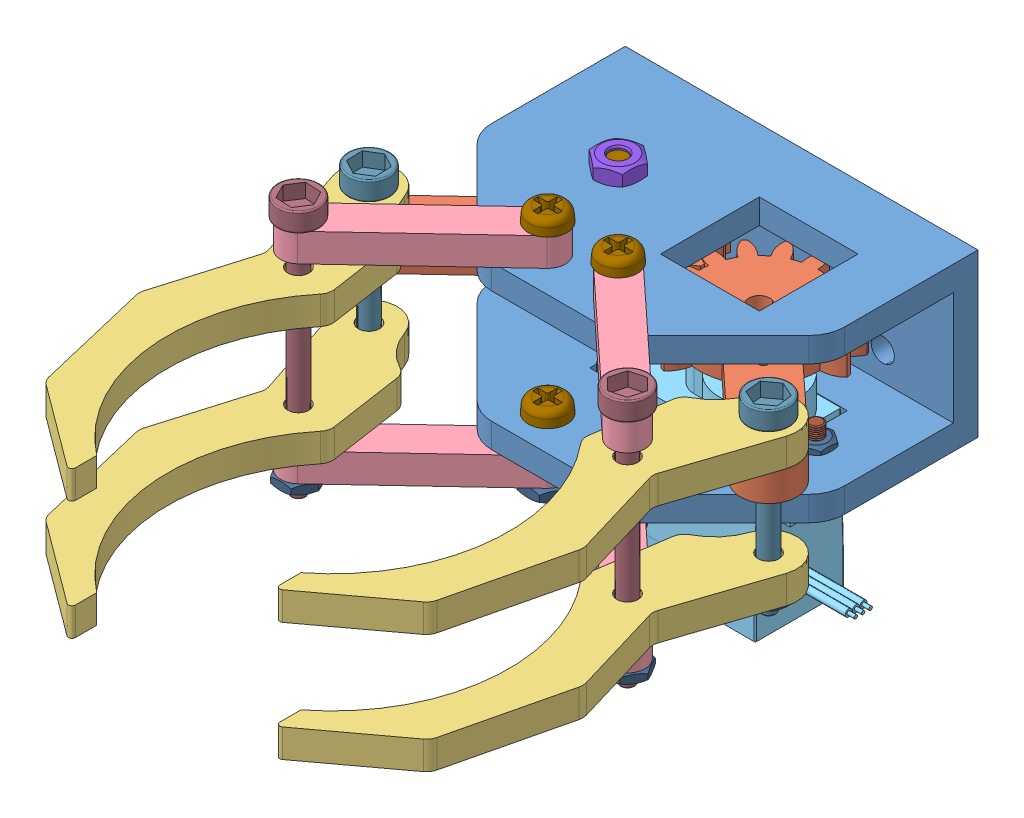
SolidWorks assembly 机械臂, configuration 默认. Lengths in mm.
Overall size (77.1 48.36 89.05).
38 component instances, 14 part files, 135 mates.
Components (placement in the parent):
- 支撑板（改）-1: 支撑板（改） [默认] at (92.699 11.5 0) x (0 0 -1) z (1 0 0) size (36 23 50)
- 齿轮传动杆-6: 齿轮传动杆 [默认] at (109.3845 -5.9575 25.747) x (0 1 0) z (0.609506 0 0.792782) size (4 39.97 22.17)
- 齿轮传动杆-7: 齿轮传动杆 [默认] at (137.3064 -6.0175 13.6459) x (0 1 0) z (0.748833 0 -0.662759) size (4 39.97 22.17)
- 机械手爪（改）-1: 机械手爪（改） [默认] at (126.8226 16.84 9.7612) x (-1 0 0) z (0 1 0) size (17.85 59.94 4)
- 机械手爪（改）-2: 机械手爪（改） [默认] at (108.6689 20.84 9.8615) x (1 0 0) z (0 -1 0) size (17.85 59.94 4)
- 连杆（改）-1: 连杆（改） [默认] at (131.861 27 39.5033) x (-0.680266 0 0.732966) z (0 -1 0) size (5 30 4)
- 连杆（改）-2: 连杆（改） [默认] at (103.5837 23 39.5535) x (0.684277 0 0.729222) z (0 1 0) size (5 30 4)
- 连杆（改）-3: 连杆（改） [默认] at (131.861 0 39.5033) x (0.680266 0 -0.732966) z (0 -1 0) size (5 30 4)
- 连杆（改）-4: 连杆（改） [默认] at (103.5837 0 39.5535) x (-0.684277 0 -0.729222) z (0 -1 0) size (5 30 4)
- 机械手爪（改）-3: 机械手爪（改） [默认] at (126.8226 0 9.7612) x (-1 0 0) z (0 1 0) size (17.85 59.94 4)
- 机械手爪（改）-4: 机械手爪（改） [默认] at (108.6689 4 9.8615) x (1 0 0) z (0 -1 0) size (17.85 59.94 4)
- SG90-2: SG90 [Default] at (126.294 -2.32 16) x (-1 0 0) z (0 0 -1) size (36.67 29.95 12.59)
  - Tower Pro 9g Micro Servo SG90-1: Tower Pro 9g Micro Servo SG90 [Default] at origin size (36.67 29.95 12.59)
- SG90 plastic Horn-1: SG90 plastic Horn [Default] at (127.699 10.84 16) x (0.605346 0 0.795962) z (-0.795962 0 0.605346) size (19.4 4 7.07)
- plain washers--product grade c gb-2: plain washers--product grade c gb [GB_FASTENER_WASHER_SMWC 3] at (107.699 17.4 16) x (-0.69769 0 0.716399) z (0 1 0) size (7 7 0.5)
- hex nuts, style 1-grades ab gb-2: hex nuts, style 1-grades ab gb [GB_FASTENER_NUT_SNAB1 M3-N] at (107.699 23 16) x (-0.923728 0 0.383049) z (0 -1 0) size (6.35 5.5 2.4)
- cross recessed cheese head screws gb-3: cross recessed cheese head screws gb [GB_CROSS_SCREWS_TYPE2 M3X12-12  H type-C] at (107.699 10.9 16) x (0 1 0) z (0 0 1) size (14.01 5.5 5.5)
- hex thin nuts-grades ab-chamfered gb-1: hex thin nuts-grades ab-chamfered gb [GB_FASTENER_NUT_STNAB M2-N] at (135.744 3.5 16) x (0.837169 0 0.546944) z (0 -1 0) size (4.62 4 1.2)
- hex thin nuts-grades ab-chamfered gb-2: hex thin nuts-grades ab-chamfered gb [GB_FASTENER_NUT_STNAB M2-N] at (108.074 3.5 16) x (0.837169 0 0.546944) z (0 -1 0) size (4.62 4 1.2)
- cross recessed countersunk head screws gb2-3: cross recessed countersunk head screws gb2 [GB_CROSS_SCREWS_TYPE10 M2X10-8.8-H1-S] at (108.074 -3.52 16) x (0 1 0) z (0.546944 0 -0.837169) size (10 3.5 3.5)
- cross recessed countersunk head screws gb2-4: cross recessed countersunk head screws gb2 [GB_CROSS_SCREWS_TYPE10 M2X10-8.8-H1-S] at (135.744 -3.52 16) x (0 1 0) z (0 0 1) size (10 3.5 3.5)
- 2.1支撑垫片-1: 2.1支撑垫片 [默认] at (107.699 19.5 16) x (1 0 0) z (0 -1 0) size (5 5 2.1)
- hex thin nuts-grades ab-chamfered gb-3: hex thin nuts-grades ab-chamfered gb [GB_FASTENER_NUT_STNAB M2.5-N] at (141.0231 -4 48.0066) x (1 0 0) z (0 1 0) size (5.77 5 1.6)
- hex thin nuts-grades ab-chamfered gb-4: hex thin nuts-grades ab-chamfered gb [GB_FASTENER_NUT_STNAB M2.5-N] at (89.4684 0 33.1069) x (0.977048 0 0.213019) z (0 1 0) size (5.77 5 1.6)
- hex thin nuts-grades ab-chamfered gb-5: hex thin nuts-grades ab-chamfered gb [GB_FASTENER_NUT_STNAB M2.5-N] at (146.0231 -1.6 33.0066) x (0.933255 0 -0.359214) z (0 -1 0) size (5.77 5 1.6)
- hex thin nuts-grades ab-chamfered gb-6: hex thin nuts-grades ab-chamfered gb [GB_FASTENER_NUT_STNAB M2.5-N] at (94.4684 -4 48.1069) x (1 0 0) z (0 1 0) size (5.77 5 1.6)
- 30限位螺栓-3: 30限位螺栓 [默认] at (141.0231 29.7 48.0066) x (-0.844413 0 -0.535692) z (-0.535692 0 0.844413) size (5.9 36.7 5.9)
- 30限位螺栓-4: 30限位螺栓 [默认] at (94.4684 29.7 48.1069) x (0.335228 0 -0.942137) z (-0.942137 0 -0.335228) size (5.9 36.7 5.9)
- 20限位螺栓-3: 20限位螺栓 [默认] at (146.0231 23.54 33.0066) x (0.648707 0 -0.761038) z (-0.761038 0 -0.648707) size (5.9 26.7 5.9)
- 20限位螺栓-4: 20限位螺栓 [默认] at (89.4684 23.54 33.1069) x (0.708583 0 -0.705627) z (-0.705627 0 -0.708583) size (5.9 26.7 5.9)
- cross recessed cheese head screws gb-5: cross recessed cheese head screws gb [GB_CROSS_SCREWS_TYPE2 M3X10-10  H type-C] at (112.699 5.5 31) x (0 -1 0) z (0 0 1) size (12.01 5.5 5.5)
- cross recessed cheese head screws gb-6: cross recessed cheese head screws gb [GB_CROSS_SCREWS_TYPE2 M3X10-10  H type-C] at (122.699 5.5 31) x (0 -1 0) z (0 0 1) size (12.01 5.5 5.5)
- cross recessed cheese head screws gb-7: cross recessed cheese head screws gb [GB_CROSS_SCREWS_TYPE2 M3X10-10  H type-C] at (122.699 29 31) x (0 -1 0) z (0 0 1) size (12.01 5.5 5.5)
- cross recessed cheese head screws gb-8: cross recessed cheese head screws gb [GB_CROSS_SCREWS_TYPE2 M3X10-10  H type-C] at (112.699 29 31) x (0 -1 0) z (0 0 1) size (12.01 5.5 5.5)
- hex thin nuts-grades ab-chamfered gb-7: hex thin nuts-grades ab-chamfered gb [GB_FASTENER_NUT_STNAB M3-N] at (122.699 17.7 31) x (1 0 0) z (0 -1 0) size (6.35 5.5 1.8)
- hex thin nuts-grades ab-chamfered gb-9: hex thin nuts-grades ab-chamfered gb [GB_FASTENER_NUT_STNAB M3-N] at (112.699 17.7 31) x (1 0 0) z (0 -1 0) size (6.35 5.5 1.8)
- hex thin nuts-grades ab-chamfered gb-11: hex thin nuts-grades ab-chamfered gb [GB_FASTENER_NUT_STNAB M3-N] at (122.699 -5.8 31) x (1 0 0) z (0 -1 0) size (6.35 5.5 1.8)
- hex thin nuts-grades ab-chamfered gb-12: hex thin nuts-grades ab-chamfered gb [GB_FASTENER_NUT_STNAB M3-N] at (112.699 -4 31) x (1 0 0) z (0 1 0) size (6.35 5.5 1.8)
Mates (geometry in assembly coordinates):
- 重合1: coincident anti-aligned: plane of 支撑板（改）-1 through (142.699 0 0) normal (0 -1 0)
- 重合2: coincident anti-aligned: plane of 支撑板（改）-1 through (142.699 23 45) normal (0 1 0); plane of 零件2-1 through (70.0462 31.0635 138.7795) normal (0 -1 0)
- 同心1: concentric aligned: cylinder of 支撑板（改）-1 through (127.699 89.5 16) axis (0 -1 0) radius 1.5; cylinder of 零件2-1 through (70.0462 81.0636 138.7795) axis (0 -1 0) radius 1.5
- 重合3: coincident anti-aligned: plane of 支撑板（改）-1 through (142.699 23 45) normal (0 1 0); plane of 零件2-2 through (70.0462 31.0635 118.7795) normal (0 -1 0)
- 同心2: concentric anti-aligned: cylinder of 支撑板（改）-1 through (107.699 89.5 16) axis (0 -1 0) radius 1.5; cylinder of 零件2-2 through (70.0462 -14.9365 118.7795) axis (0 1 0) radius 1.5
- 重合6: coincident anti-aligned: plane of 支撑板（改）-1 through (142.699 23 45) normal (0 1 0); plane of 零件2-3 through (70.0462 31.0635 118.7795) normal (0 -1 0)
- 同心3: concentric anti-aligned: cylinder of 支撑板（改）-1 through (107.699 89.5 16) axis (0 -1 0) radius 1.5; cylinder of 零件2-3 through (70.0462 -14.9365 118.7795) axis (0 1 0) radius 1.5
- 同心9: concentric aligned: cylinder of 支撑板（改）-1 through (107.699 89.5 16) axis (0 -1 0) radius 1.5; cylinder of 齿轮传动杆-6 through (107.699 62.9001 16) axis (0 -1 0) radius 1.5
- 重合13: coincident anti-aligned: plane of 齿轮传动杆-7 through (127.699 16.84 16) normal (0 1 0); plane of 机械手爪（改）-2 through (118.6269 16.84 65.7764) normal (0 -1 0)
- 同心11: concentric aligned: cylinder of 齿轮传动杆-6 through (89.4684 12.9 33.1069) axis (0 1 0) radius 1.5; cylinder of 机械手爪（改）-2 through (89.4684 16.84 33.1069) axis (0 1 0) radius 1.5
- 重合14: coincident anti-aligned: plane of 齿轮传动杆-7 through (127.699 16.84 16) normal (0 1 0); plane of 机械手爪（改）-1 through (116.8646 16.84 65.6761) normal (0 -1 0)
- 同心12: concentric anti-aligned: cylinder of 齿轮传动杆-7 through (146.0231 12.84 33.0066) axis (0 1 0) radius 1.5; cylinder of 机械手爪（改）-1 through (146.0231 20.84 33.0066) axis (0 -1 0) radius 1.5
- 同心13: concentric anti-aligned: cylinder of 机械手爪（改）-1 through (141.0231 20.84 48.0066) axis (0 -1 0) radius 1.5; cylinder of 连杆（改）-1 through (141.0231 23 48.0066) axis (0 1 0) radius 1.5
- 同心14: concentric anti-aligned: cylinder of 支撑板（改）-1 through (122.699 89.5 31) axis (0 -1 0) radius 1.5; cylinder of 连杆（改）-1 through (122.699 23 31) axis (0 1 0) radius 1.5
- 同心15: concentric anti-aligned: cylinder of 机械手爪（改）-2 through (94.4684 16.84 48.1069) axis (0 1 0) radius 1.5; cylinder of 连杆（改）-2 through (94.4684 27 48.1069) axis (0 -1 0) radius 1.5
- 同心16: concentric aligned: cylinder of 支撑板（改）-1 through (112.699 89.5 31) axis (0 -1 0) radius 1.5; cylinder of 连杆（改）-2 through (112.699 27 31) axis (0 -1 0) radius 1.5
- 重合17: coincident anti-aligned: plane of 连杆（改）-3 through (122.699 0 31) normal (0 1 0); plane of 机械手爪（改）-3 through (116.8646 0 65.6761) normal (0 -1 0)
- 同心19: concentric anti-aligned: cylinder of 连杆（改）-3 through (141.0231 -4 48.0066) axis (0 1 0) radius 1.5; cylinder of 机械手爪（改）-3 through (141.0231 4 48.0066) axis (0 -1 0) radius 1.5
- 重合20: coincident anti-aligned: plane of 连杆（改）-4 through (94.4684 0 48.1069) normal (0 1 0); plane of 机械手爪（改）-4 through (118.6269 0 65.7764) normal (0 -1 0)
- 同心24: concentric anti-aligned: cylinder of 支撑板（改）-1 through (122.699 89.5 31) axis (0 -1 0) radius 1.5; cylinder of 连杆（改）-3 through (122.699 -4 31) axis (0 1 0) radius 1.5
- 同心25: concentric anti-aligned: cylinder of 支撑板（改）-1 through (112.699 89.5 31) axis (0 -1 0) radius 1.5; cylinder of 连杆（改）-4 through (112.699 -4 31) axis (0 1 0) radius 1.5
- 同心30: concentric anti-aligned: cylinder of 机械手爪（改）-1 through (141.0231 20.84 48.0066) axis (0 -1 0) radius 1.5; cylinder of 连杆-2 through (50.1174 -3 156.1886) axis (0 1 0) radius 1.5
- 同心31: concentric anti-aligned: cylinder of 机械手爪（改）-3 through (141.0231 4 48.0066) axis (0 -1 0) radius 1.5; cylinder of 连杆-2 through (50.1174 -3 156.1886) axis (0 1 0) radius 1.5
- 同心32: concentric anti-aligned: cylinder of 机械手爪（改）-1 through (146.0231 20.84 33.0066) axis (0 -1 0) radius 1.5; cylinder of 连杆-4 through (62.6978 0 163.3985) axis (0 1 0) radius 1.5
- 同心33: concentric anti-aligned: cylinder of 机械手爪（改）-3 through (146.0231 4 33.0066) axis (0 -1 0) radius 1.5; cylinder of 连杆-4 through (62.6978 0 163.3985) axis (0 1 0) radius 1.5
- 同心34: concentric anti-aligned: cylinder of 机械手爪（改）-4 through (89.4684 0 33.1069) axis (0 1 0) radius 1.5; cylinder of 连杆-5 through (62.5628 32 94.1848) axis (0 -1 0) radius 1.5
- 同心35: concentric anti-aligned: cylinder of 机械手爪（改）-2 through (89.4684 16.84 33.1069) axis (0 1 0) radius 1.5; cylinder of 连杆-5 through (62.5628 32 94.1848) axis (0 -1 0) radius 1.5
- 同心36: concentric anti-aligned: cylinder of 机械手爪（改）-4 through (94.4684 0 48.1069) axis (0 1 0) radius 1.5; cylinder of 连杆-6 through (49.9764 29.5 101.3843) axis (0 -1 0) radius 1.5
- 同心37: concentric anti-aligned: cylinder of 机械手爪（改）-2 through (94.4684 16.84 48.1069) axis (0 1 0) radius 1.5; cylinder of 连杆-6 through (49.9764 29.5 101.3843) axis (0 -1 0) radius 1.5
- 重合22: coincident aligned: plane of 机械手爪（改）-3 through (116.8646 0 65.6761) normal (0 -1 0); plane of 连杆-4 through (62.6978 0 163.3985) normal (0 -1 0)
- 重合23: coincident aligned: plane of 连杆（改）-3 through (122.699 -4 31) normal (0 -1 0); plane of 连杆-2 through (50.1174 -3 156.1886) normal (0 -1 0)
- 重合25: coincident aligned: plane of 连杆-5 through (62.5628 0 94.1848) normal (0 -1 0); plane of 机械手爪（改）-4 through (118.6269 0 65.7764) normal (0 -1 0)
- 重合26: coincident aligned: plane of 连杆（改）-4 through (94.4684 -4 48.1069) normal (0 -1 0); plane of 连杆-6 through (49.9764 -2.5 101.3843) normal (0 -1 0)
- 同心39: concentric aligned: cylinder of 连杆（改）-4 through (94.4684 -4 48.1069) axis (0 1 0) radius 1.5; cylinder of 机械手爪（改）-4 through (94.4684 0 48.1069) axis (0 1 0) radius 1.5
- 齿轮配合3: gear = 20 : 20 mm: circle of 零件2-5; circle of 零件2-4
- 重合32: coincident anti-aligned: plane of 支撑板（改）-1 through (142.699 0 0) normal (0 -1 0); plane of SG90-2/Tower Pro 9g Micro Servo SG90-1 through (138.064 0 9.705) normal (0 1 0)
- 同心41: concentric aligned: cylinder of 支撑板（改）-1 through (108.074 10 16) axis (0 -1 0) radius 1; cylinder of SG90-2/Tower Pro 9g Micro Servo SG90-1 through (108.074 8.34 16) axis (0 -1 0) radius 0.975
- 同心42: concentric aligned: cylinder of 支撑板（改）-1 through (135.744 10 16) axis (0 -1 0) radius 1; cylinder of SG90-2/Tower Pro 9g Micro Servo SG90-1 through (135.744 8.34 16) axis (0 -1 0) radius 0.975
- 重合35: coincident anti-aligned: plane of SG90-2/Tower Pro 9g Micro Servo SG90-1 through (127.699 11.29 16) normal (0 1 0); plane of SG90 plastic Horn-1 through (128.4526 11.29 16.991) normal (0 -1 0)
- 同心44: concentric aligned: cylinder of SG90-2/Tower Pro 9g Micro Servo SG90-1 through (127.699 7.34 16) axis (0 1 0) radius 2.3; cylinder of SG90 plastic Horn-1 through (127.699 65.84 16) axis (0 1 0) radius 2.375
- 重合42: coincident anti-aligned: plane of 支撑板（改）-1 through (142.699 19.5 45) normal (0 -1 0); plane of plain washers--product grade c gb-5 through (67.0462 25.4 138.7795) normal (0 1 0)
- 同心45: concentric anti-aligned: cylinder of 支撑板（改）-1 through (127.699 89.5 16) axis (0 -1 0) radius 1.5; cylinder of plain washers--product grade c gb-5 through (67.0462 24.9 138.7795) axis (0 1 0) radius 1.7
- 重合44: coincident anti-aligned: plane of 齿轮传动杆-7 through (127.699 16.84 16) normal (0 1 0); plane of plain washers--product grade c gb-5 through (67.0462 24.9 138.7795) normal (0 -1 0)
- 同心46: concentric anti-aligned: cylinder of 支撑板（改）-1 through (107.699 89.5 16) axis (0 -1 0) radius 1.5; cylinder of plain washers--product grade c gb-2 through (107.699 16.9 16) axis (0 1 0) radius 1.7
- 重合46: coincident anti-aligned: plane of 齿轮传动杆-6 through (107.699 16.9 16) normal (0 1 0); plane of plain washers--product grade c gb-5 through (67.0462 24.9 138.7795) normal (0 -1 0)
- 重合47: coincident anti-aligned: plane of 支撑板（改）-1 through (142.699 23 45) normal (0 1 0); plane of 连杆（改）-1 through (141.0231 23 48.0066) normal (0 -1 0)
- 重合48: coincident anti-aligned: plane of 支撑板（改）-1 through (142.699 23 45) normal (0 1 0); plane of 连杆（改）-2 through (94.4684 23 48.1069) normal (0 -1 0)
- 重合49: coincident anti-aligned: plane of 齿轮传动杆-6 through (107.699 12.9 16) normal (0 -1 0); plane of cross recessed cheese head screws gb-1 through (67.0462 13.4 116.9795) normal (0 1 0)
- 同心47: concentric anti-aligned: cylinder of 支撑板（改）-1 through (107.699 89.5 16) axis (0 -1 0) radius 1.5; cylinder of cross recessed cheese head screws gb-1 through (67.0462 15.9158 118.7795) axis (0 1 0) radius 1.5
- 重合51: coincident anti-aligned: plane of 齿轮传动杆-6 through (107.699 12.9 16) normal (0 -1 0); plane of cross recessed cheese head screws gb-3 through (105.899 12.9 16) normal (0 1 0)
- 同心50: concentric anti-aligned: cylinder of 支撑板（改）-1 through (107.699 89.5 16) axis (0 -1 0) radius 1.5; cylinder of cross recessed cheese head screws gb-3 through (107.699 15.4158 16) axis (0 1 0) radius 1.5
- 重合52: coincident anti-aligned: plane of 支撑板（改）-1 through (142.699 23 45) normal (0 1 0); plane of hex nuts, style 1-grades ab gb-2 through (109.8057 23 21.0805) normal (0 -1 0)
- 同心51: concentric anti-aligned: cylinder of hex nuts, style 1-grades ab gb-2 through (107.699 25.4 16) axis (0 -1 0) radius 1.2295; cylinder of cross recessed cheese head screws gb-3 through (107.699 15.4158 16) axis (0 1 0) radius 1.5
- 重合54: coincident anti-aligned: plane of SG90-2/Tower Pro 9g Micro Servo SG90-1 through (110.394 -2.32 9.705) normal (0 -1 0); circle of cross recessed countersunk head screws gb2-2
- 同心52: concentric anti-aligned: cylinder of SG90-2/Tower Pro 9g Micro Servo SG90-1 through (108.074 8.34 16) axis (0 -1 0) radius 0.975; cylinder of cross recessed countersunk head screws gb2-2 through (67.0462 0.9958 120.5595) axis (0 1 0) radius 1
- 重合55: coincident anti-aligned: plane of SG90-2/Tower Pro 9g Micro Servo SG90-1 through (138.064 -2.32 9.705) normal (0 -1 0); circle of cross recessed countersunk head screws gb2-1
- 同心53: concentric anti-aligned: cylinder of SG90-2/Tower Pro 9g Micro Servo SG90-1 through (135.744 8.34 16) axis (0 -1 0) radius 0.975; cylinder of cross recessed countersunk head screws gb2-1 through (67.0462 0.9958 148.2295) axis (0 1 0) radius 1.75
- 重合56: coincident anti-aligned: plane of 支撑板（改）-1 through (142.699 3.5 3.5) normal (0 1 0); plane of hex thin nuts-grades ab-chamfered gb-2 through (106.2678 3.5 12.431) normal (0 -1 0)
- 同心54: concentric aligned: circle of cross recessed countersunk head screws gb2-2; cylinder of hex thin nuts-grades ab-chamfered gb-2 through (108.074 4.7 16) axis (0 -1 0) radius 0.7835
- 重合57: coincident anti-aligned: plane of SG90-2/Tower Pro 9g Micro Servo SG90-1 through (110.394 -2.32 9.705) normal (0 -1 0); circle of cross recessed countersunk head screws gb2-3
- 同心55: concentric aligned: cylinder of SG90-2/Tower Pro 9g Micro Servo SG90-1 through (108.074 8.34 16) axis (0 -1 0) radius 0.975; circle of cross recessed countersunk head screws gb2-3
- 重合58: coincident anti-aligned: plane of SG90-2/Tower Pro 9g Micro Servo SG90-1 through (138.064 -2.32 9.705) normal (0 -1 0); circle of cross recessed countersunk head screws gb2-4
- 同心56: concentric anti-aligned: cylinder of SG90-2/Tower Pro 9g Micro Servo SG90-1 through (135.744 8.34 16) axis (0 -1 0) radius 0.975; cylinder of cross recessed countersunk head screws gb2-4 through (135.744 0.9958 16) axis (0 1 0) radius 1.75
- 重合59: coincident anti-aligned: plane of 支撑板（改）-1 through (142.699 3.5 3.5) normal (0 1 0); plane of hex thin nuts-grades ab-chamfered gb-1 through (133.9378 3.5 12.431) normal (0 -1 0)
- 同心57: concentric aligned: cylinder of hex thin nuts-grades ab-chamfered gb-1 through (135.744 4.7 16) axis (0 -1 0) radius 0.7835; circle of cross recessed countersunk head screws gb2-4
- 重合61: coincident anti-aligned: plane of 齿轮传动杆-6 through (107.699 16.9 16) normal (0 1 0); plane of plain washers--product grade c gb-2 through (107.699 16.9 16) normal (0 -1 0)
- 重合63: coincident anti-aligned: plane of 齿轮传动杆-7 through (127.699 12.84 16) normal (0 -1 0); plane of SG90 plastic Horn-1 through (129.8389 12.84 18.8137) normal (0 1 0)
- 重合64: coincident anti-aligned: plane of 支撑板（改）-1 through (142.699 0 0) normal (0 -1 0); plane of 连杆（改）-4 through (94.4684 0 48.1069) normal (0 1 0)
- 重合66: coincident anti-aligned: plane of 支撑板（改）-1 through (142.699 0 0) normal (0 -1 0); plane of 连杆（改）-3 through (122.699 0 31) normal (0 1 0)
- 重合67: coincident anti-aligned: plane of 连杆（改）-3 through (122.699 -4 31) normal (0 -1 0); circle of slotted ctsk screws waisted shank gb-3
- 重合68: coincident anti-aligned: plane of 连杆（改）-1 through (141.0231 27 48.0066) normal (0 1 0); plane of slotted screws with waisted shank gb-5 through (49.0811 23.9 146.4039) normal (0 -1 0)
- 重合71: coincident anti-aligned: plane of 支撑板（改）-1 through (142.699 19.5 45) normal (0 -1 0); plane of 0.1垫片-1 through (107.699 19.5 16) normal (0 1 0)
- 同心58: concentric aligned: cylinder of cross recessed cheese head screws gb-3 through (107.699 15.4158 16) axis (0 1 0) radius 1.5; cylinder of 0.1垫片-1 through (107.699 17.4 16) axis (0 1 0) radius 1.5
- 重合72: coincident anti-aligned: plane of plain washers--product grade c gb-2 through (107.699 17.4 16) normal (0 1 0); plane of 0.1垫片-1 through (107.699 17.4 16) normal (0 -1 0)
- 重合73: coincident anti-aligned: plane of 连杆（改）-3 through (122.699 -4 31) normal (0 -1 0); plane of 25限位螺栓-1 through (31.7301 -4 138.5188) normal (0 1 0)
- 同心59: concentric anti-aligned: cylinder of 连杆（改）-3 through (141.0231 -4 48.0066) axis (0 1 0) radius 1.5; cylinder of 25限位螺栓-1 through (31.7301 26 138.5188) axis (0 -1 0) radius 1.5
- 同心61: concentric aligned: cylinder of 机械手爪（改）-1 through (141.0231 20.84 48.0066) axis (0 -1 0) radius 1.5; cylinder of 25限位螺栓-1 through (31.7301 26 138.5188) axis (0 -1 0) radius 1.5
- 重合76: coincident anti-aligned: plane of 25限位螺栓-1 through (31.7301 26 138.5188) normal (0 1 0); plane of hex thin nuts-grades ab-chamfered gb-3 through (136.693 -5.6 50.5066) normal (0 -1 0)
- 同心63: concentric anti-aligned: cylinder of 25限位螺栓-1 through (31.7301 31 138.5188) axis (0 -1 0) radius 1.25; cylinder of hex thin nuts-grades ab-chamfered gb-3 through (141.0231 -5.6 48.0066) axis (0 1 0) radius 1.0065
- 重合77: coincident anti-aligned: plane of 机械手爪（改）-4 through (118.6269 0 65.7764) normal (0 -1 0); plane of 25限位螺栓1-1 through (45.1123 0 106.7836) normal (0 1 0)
- 同心64: concentric anti-aligned: cylinder of 机械手爪（改）-4 through (89.4684 0 33.1069) axis (0 1 0) radius 1.5; cylinder of 25限位螺栓1-1 through (45.1123 25 106.7836) axis (0 -1 0) radius 1.5
- 同心65: concentric anti-aligned: cylinder of 齿轮传动杆-6 through (89.4684 12.9 33.1069) axis (0 1 0) radius 1.5; cylinder of 25限位螺栓1-1 through (45.1123 25 106.7836) axis (0 -1 0) radius 1.5
- 重合78: coincident anti-aligned: plane of hex thin nuts-grades ab-chamfered gb-4 through (84.7051 -1.6 34.6271) normal (0 -1 0); plane of 25限位螺栓1-1 through (45.1123 25 106.7836) normal (0 1 0)
- 同心66: concentric aligned: circle of hex thin nuts-grades ab-chamfered gb-4; cylinder of 25限位螺栓1-1 through (45.1123 30 106.7836) axis (0 -1 0) radius 1.25
- 同心67: concentric anti-aligned: cylinder of 连杆（改）-4 through (94.4684 -4 48.1069) axis (0 1 0) radius 1.5; cylinder of 25限位螺栓-2 through (31.7089 55 119.2025) axis (0 -1 0) radius 1.5
- 重合80: coincident anti-aligned: plane of hex thin nuts-grades ab-chamfered gb-6 through (90.1383 -5.6 50.6069) normal (0 -1 0); plane of 25限位螺栓-2 through (31.7089 55 119.2025) normal (0 1 0)
- 同心68: concentric anti-aligned: cylinder of hex thin nuts-grades ab-chamfered gb-6 through (94.4684 -5.6 48.1069) axis (0 1 0) radius 1.0065; cylinder of 25限位螺栓-2 through (31.7089 60 119.2025) axis (0 -1 0) radius 1.25
- 重合81: coincident anti-aligned: plane of 机械手爪（改）-3 through (116.8646 0 65.6761) normal (0 -1 0); plane of 25限位螺栓1-2 through (43.4542 0 147.0508) normal (0 1 0)
- 同心69: concentric aligned: cylinder of 机械手爪（改）-3 through (146.0231 4 33.0066) axis (0 -1 0) radius 1.5; cylinder of 25限位螺栓1-2 through (43.4542 25 147.0508) axis (0 -1 0) radius 1.5
- 重合82: coincident anti-aligned: plane of hex thin nuts-grades ab-chamfered gb-5 through (141.084 -1.6 32.2289) normal (0 -1 0); plane of 25限位螺栓1-2 through (43.4542 25 147.0508) normal (0 1 0)
- 同心70: concentric aligned: cylinder of hex thin nuts-grades ab-chamfered gb-5 through (146.0231 0 33.0066) axis (0 -1 0) radius 1.0065; cylinder of 25限位螺栓1-2 through (43.4542 30 147.0508) axis (0 -1 0) radius 1.25
- 同心71: concentric anti-aligned: cylinder of 齿轮传动杆-7 through (146.0231 12.84 33.0066) axis (0 1 0) radius 1.5; cylinder of 25限位螺栓1-2 through (43.4542 25 147.0508) axis (0 -1 0) radius 1.5
- 重合83: coincident aligned: plane of 连杆（改）-2 through (94.4684 27 48.1069) normal (0 1 0); plane of 25限位螺栓-2 through (31.7089 25 119.2025) normal (0 1 0)
- 重合84: coincident anti-aligned: plane of 机械手爪（改）-1 through (116.8646 20.84 65.6761) normal (0 1 0); plane of 25限位螺栓1-3 through (146.0231 20.84 33.0066) normal (0 -1 0)
- 同心72: concentric anti-aligned: cylinder of 机械手爪（改）-1 through (146.0231 20.84 33.0066) axis (0 -1 0) radius 1.5; cylinder of 25限位螺栓1-3 through (146.0231 0.84 33.0066) axis (0 1 0) radius 1.25
- 同心73: concentric anti-aligned: cylinder of 机械手爪（改）-3 through (146.0231 4 33.0066) axis (0 -1 0) radius 1.5; cylinder of 25限位螺栓1-3 through (146.0231 0.84 33.0066) axis (0 1 0) radius 1.25
- 同心74: concentric anti-aligned: cylinder of hex thin nuts-grades ab-chamfered gb-5 through (146.0231 0 33.0066) axis (0 -1 0) radius 1.0065; cylinder of 25限位螺栓1-3 through (146.0231 -3.16 33.0066) axis (0 1 0) radius 1
- 重合86: coincident anti-aligned: plane of 连杆（改）-1 through (141.0231 27 48.0066) normal (0 1 0); plane of 25限位螺栓-3 through (141.0231 27 48.0066) normal (0 -1 0)
- 同心75: concentric aligned: cylinder of 连杆（改）-1 through (141.0231 23 48.0066) axis (0 1 0) radius 1.5; cylinder of 25限位螺栓-3 through (141.0231 -3 48.0066) axis (0 1 0) radius 1.25
- 重合87: coincident anti-aligned: plane of hex thin nuts-grades ab-chamfered gb-3 through (136.693 -4 50.5066) normal (0 1 0); plane of 连杆（改）-3 through (122.699 -4 31) normal (0 -1 0)
- 同心76: concentric aligned: cylinder of hex thin nuts-grades ab-chamfered gb-3 through (141.0231 -5.6 48.0066) axis (0 1 0) radius 1.0065; cylinder of 25限位螺栓-3 through (141.0231 -7 48.0066) axis (0 1 0) radius 1
- 重合88: coincident anti-aligned: plane of 连杆（改）-2 through (94.4684 27 48.1069) normal (0 1 0); plane of 25限位螺栓-4 through (94.4684 27 48.1069) normal (0 -1 0)
- 同心77: concentric anti-aligned: cylinder of 连杆（改）-2 through (94.4684 27 48.1069) axis (0 -1 0) radius 1.5; cylinder of 25限位螺栓-4 through (94.4684 -3 48.1069) axis (0 1 0) radius 1.25
- 同心79: concentric aligned: cylinder of 连杆（改）-4 through (94.4684 -4 48.1069) axis (0 1 0) radius 1.5; cylinder of 25限位螺栓-4 through (94.4684 -3 48.1069) axis (0 1 0) radius 1.25
- 重合90: coincident anti-aligned: plane of hex thin nuts-grades ab-chamfered gb-6 through (90.1383 -4 50.6069) normal (0 1 0); plane of 连杆（改）-4 through (94.4684 -4 48.1069) normal (0 -1 0)
- 同心80: concentric aligned: cylinder of hex thin nuts-grades ab-chamfered gb-6 through (94.4684 -5.6 48.1069) axis (0 1 0) radius 1.0065; cylinder of 25限位螺栓-4 through (94.4684 -7 48.1069) axis (0 1 0) radius 1
- 重合91: coincident anti-aligned: plane of 机械手爪（改）-2 through (118.6269 20.84 65.7764) normal (0 1 0); plane of 25限位螺栓1-4 through (89.4684 20.84 33.1069) normal (0 -1 0)
- 同心81: concentric aligned: cylinder of 机械手爪（改）-2 through (89.4684 16.84 33.1069) axis (0 1 0) radius 1.5; cylinder of 25限位螺栓1-4 through (89.4684 0.84 33.1069) axis (0 1 0) radius 1.25
- 同心82: concentric aligned: cylinder of 机械手爪（改）-4 through (89.4684 0 33.1069) axis (0 1 0) radius 1.5; cylinder of 25限位螺栓1-4 through (89.4684 0.84 33.1069) axis (0 1 0) radius 1.25
- 同心83: concentric aligned: cylinder of hex thin nuts-grades ab-chamfered gb-4 through (89.4684 -1.6 33.1069) axis (0 1 0) radius 1.0065; cylinder of 25限位螺栓1-4 through (89.4684 -3.16 33.1069) axis (0 1 0) radius 1
- 同心84: concentric anti-aligned: cylinder of 机械手爪（改）-3 through (141.0231 4 48.0066) axis (0 -1 0) radius 1.5; cylinder of 25限位螺栓-3 through (141.0231 -3 48.0066) axis (0 1 0) radius 1.25
- 重合93: coincident anti-aligned: plane of 连杆（改）-1 through (141.0231 27 48.0066) normal (0 1 0); plane of cross recessed cheese head screws gb-7 through (124.499 27 31) normal (0 -1 0)
- 同心85: concentric anti-aligned: cylinder of 连杆（改）-1 through (122.699 23 31) axis (0 1 0) radius 1.5; cylinder of cross recessed cheese head screws gb-7 through (122.699 24.4842 31) axis (0 -1 0) radius 1.5
- 重合94: coincident anti-aligned: plane of 连杆（改）-2 through (94.4684 27 48.1069) normal (0 1 0); plane of cross recessed cheese head screws gb-8 through (114.499 27 31) normal (0 -1 0)
- 同心86: concentric aligned: cylinder of 连杆（改）-2 through (112.699 27 31) axis (0 -1 0) radius 1.5; cylinder of cross recessed cheese head screws gb-8 through (112.699 24.4842 31) axis (0 -1 0) radius 1.5
- 重合95: coincident anti-aligned: plane of 支撑板（改）-1 through (142.699 3.5 3.5) normal (0 1 0); plane of cross recessed cheese head screws gb-5 through (114.499 3.5 31) normal (0 -1 0)
- 同心87: concentric aligned: cylinder of 支撑板（改）-1 through (112.699 10 31) axis (0 -1 0) radius 1.5; cylinder of cross recessed cheese head screws gb-5 through (112.699 0.9842 31) axis (0 -1 0) radius 1.5
- 重合96: coincident anti-aligned: plane of 支撑板（改）-1 through (142.699 3.5 3.5) normal (0 1 0); plane of cross recessed cheese head screws gb-6 through (124.499 3.5 31) normal (0 -1 0)
- 同心88: concentric aligned: cylinder of 支撑板（改）-1 through (122.699 10 31) axis (0 -1 0) radius 1.5; cylinder of cross recessed cheese head screws gb-6 through (122.699 0.9842 31) axis (0 -1 0) radius 1.5
- 重合97: coincident anti-aligned: plane of 连杆（改）-1 through (141.0231 23 48.0066) normal (0 -1 0); plane of hex thin nuts-grades ab-chamfered gb-8 through (49.3097 21 139.0947) normal (0 1 0)
- 同心89: concentric aligned: cylinder of 机械手爪-1 through (24.7049 20.84 116.6046) axis (0 -1 0) radius 23; cone of hex thin nuts-grades ab-chamfered gb-10 through (26.0265 16.84 126.2247) axis (0 -1 0)
- 重合98: coincident anti-aligned: plane of 机械手爪（改）-1 through (116.8646 16.84 65.6761) normal (0 -1 0); plane of hex thin nuts-grades ab-chamfered gb-10 through (26.0538 16.84 129.4) normal (0 1 0)
- 重合99: coincident anti-aligned: plane of 支撑板（改）-1 through (142.699 19.5 45) normal (0 -1 0); plane of hex thin nuts-grades ab-chamfered gb-7 through (117.9358 19.5 28.25) normal (0 1 0)
- 同心90: concentric aligned: cylinder of cross recessed cheese head screws gb-7 through (122.699 24.4842 31) axis (0 -1 0) radius 1.5; cylinder of hex thin nuts-grades ab-chamfered gb-7 through (122.699 19.5 31) axis (0 -1 0) radius 1.2295
- 重合103: coincident anti-aligned: plane of 支撑板（改）-1 through (142.699 19.5 45) normal (0 -1 0); plane of hex thin nuts-grades ab-chamfered gb-9 through (107.9358 19.5 28.25) normal (0 1 0)
- 同心91: concentric aligned: cylinder of cross recessed cheese head screws gb-8 through (112.699 24.4842 31) axis (0 -1 0) radius 1.5; cylinder of hex thin nuts-grades ab-chamfered gb-9 through (112.699 19.5 31) axis (0 -1 0) radius 1.2295
- 重合105: coincident anti-aligned: plane of 连杆（改）-4 through (94.4684 -4 48.1069) normal (0 -1 0); plane of hex thin nuts-grades ab-chamfered gb-12 through (107.9358 -4 33.75) normal (0 1 0)
- 同心92: concentric anti-aligned: cylinder of cross recessed cheese head screws gb-5 through (112.699 0.9842 31) axis (0 -1 0) radius 1.5; cylinder of hex thin nuts-grades ab-chamfered gb-12 through (112.699 -5.8 31) axis (0 1 0) radius 1.2295
- 重合106: coincident anti-aligned: plane of 连杆（改）-3 through (122.699 -4 31) normal (0 -1 0); plane of hex thin nuts-grades ab-chamfered gb-11 through (117.9358 -4 28.25) normal (0 1 0)
- 同心93: concentric aligned: cylinder of cross recessed cheese head screws gb-6 through (122.699 0.9842 31) axis (0 -1 0) radius 1.5; cylinder of hex thin nuts-grades ab-chamfered gb-11 through (122.699 -4 31) axis (0 -1 0) radius 1.2295
- 重合107: coincident aligned: plane of 机械手爪（改）-4 through (118.6269 0 65.7764) normal (0 -1 0); circle of hex thin nuts-grades ab-chamfered gb-4
- 重合108: coincident anti-aligned: plane of 机械手爪（改）-3 through (116.8646 0 65.6761) normal (0 -1 0); plane of hex thin nuts-grades ab-chamfered gb-5 through (141.084 0 32.2289) normal (0 1 0)
- 同心94: concentric aligned: cylinder of hex thin nuts-grades ab-chamfered gb-2 through (108.074 4.7 16) axis (0 -1 0) radius 0.7835; circle of cross recessed countersunk head screws gb2-3
- 重合109: coincident anti-aligned: plane of 支撑板（改）-1 through (142.699 23 0) normal (0 0 -1)
- 同心103: concentric anti-aligned: cylinder of 齿轮传动杆-7 through (127.699 62.8401 16) axis (0 -1 0) radius 1.5; cylinder of SG90 plastic Horn-1 through (127.699 65.84 16) axis (0 1 0) radius 1.245
